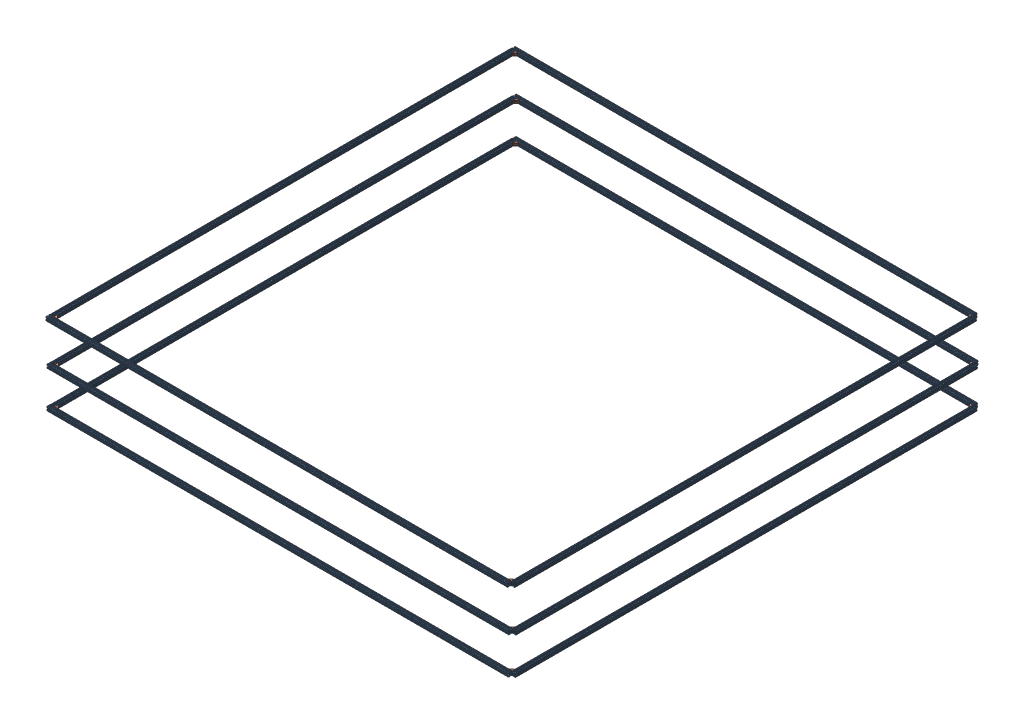
SolidWorks assembly Assem3, configuration Default. Lengths in mm.
Overall size (3082.56 533.4 3103.82).
315 component instances, 2 part files, 0 mates.
Components (placement in the parent):
- Rack Level-1: Rack Level [Default] at (101.9555 1672.9434 1770.6938) size (3070.95 28.09 3097.47)
  - big_connector_rod_24in-1: big_connector_rod_24in [Default] at origin size (25.4 25.4 3048)
    - connector_rod-1: connector_rod [Default] at (118.4239 27.3588 26.3342) size (25.4 25.4 127)
    - connector_rod-2: connector_rod [Default] at (118.4239 27.3588 -100.6658) size (25.4 25.4 127)
    - connector_rod-3: connector_rod [Default] at (118.4239 27.3588 -227.6658) size (25.4 25.4 127)
    - connector_rod-4: connector_rod [Default] at (118.4239 27.3588 -354.6658) size (25.4 25.4 127)
    - connector_rod-5: connector_rod [Default] at (118.4239 27.3588 153.3342) size (25.4 25.4 127)
    - connector_rod-6: connector_rod [Default] at (118.4239 27.3588 280.3342) size (25.4 25.4 127)
    - connector_rod-7: connector_rod [Default] at (118.4239 27.3588 407.3342) size (25.4 25.4 127)
    - connector_rod-8: connector_rod [Default] at (118.4239 27.3588 -481.6658) size (25.4 25.4 127)
    - connector_rod-9: connector_rod [Default] at (118.4239 27.3588 -608.6658) size (25.4 25.4 127)
    - connector_rod-10: connector_rod [Default] at (118.4239 27.3588 -862.6658) size (25.4 25.4 127)
    - connector_rod-11: connector_rod [Default] at (118.4239 27.3588 -735.6658) size (25.4 25.4 127)
    - connector_rod-12: connector_rod [Default] at (118.4239 27.3588 788.3342) size (25.4 25.4 127)
    - connector_rod-13: connector_rod [Default] at (118.4239 27.3588 534.3342) size (25.4 25.4 127)
    - connector_rod-14: connector_rod [Default] at (118.4239 27.3588 915.3342) x (-1 0 0) z (0 0 -1) size (25.4 25.4 127)
    - connector_rod-15: connector_rod [Default] at (118.4239 27.3588 915.3342) size (25.4 25.4 127)
    - connector_rod-16: connector_rod [Default] at (118.4239 27.3588 661.3342) size (25.4 25.4 127)
    - connector_rod-17: connector_rod [Default] at (118.4239 27.3588 1042.3342) x (-1 0 0) z (0 0 -1) size (25.4 25.4 127)
    - connector_rod-18: connector_rod [Default] at (118.4239 27.3588 1296.3342) size (25.4 25.4 127)
    - connector_rod-19: connector_rod [Default] at (118.4239 27.3588 -1116.6658) x (-1 0 0) z (0 0 -1) size (25.4 25.4 127)
    - connector_rod-20: connector_rod [Default] at (118.4239 27.3588 -1370.6658) x (-1 0 0) z (0 0 -1) size (25.4 25.4 127)
    - connector_rod-21: connector_rod [Default] at (118.4239 27.3588 1296.3342) x (-1 0 0) z (0 0 -1) size (25.4 25.4 127)
    - connector_rod-22: connector_rod [Default] at (118.4239 27.3588 -1243.6658) x (-1 0 0) z (0 0 -1) size (25.4 25.4 127)
    - connector_rod-23: connector_rod [Default] at (118.4239 27.3588 1423.3342) x (-1 0 0) z (0 0 -1) size (25.4 25.4 127)
    - connector_rod-24: connector_rod [Default] at (118.4239 27.3588 1550.3342) x (-1 0 0) z (0 0 -1) size (25.4 25.4 127)
  - big_connector_rod_24in-5: big_connector_rod_24in [Default] at (1475.8697 0 1807.1242) x (0 0 -1) z (1 0 0) size (25.4 25.4 3048)
    - connector_rod-1: connector_rod [Default] at (118.4239 27.3588 26.3342) size (25.4 25.4 127)
    - connector_rod-2: connector_rod [Default] at (118.4239 27.3588 -100.6658) size (25.4 25.4 127)
    - connector_rod-3: connector_rod [Default] at (118.4239 27.3588 -227.6658) size (25.4 25.4 127)
    - connector_rod-4: connector_rod [Default] at (118.4239 27.3588 -354.6658) size (25.4 25.4 127)
    - connector_rod-5: connector_rod [Default] at (118.4239 27.3588 153.3342) size (25.4 25.4 127)
    - connector_rod-6: connector_rod [Default] at (118.4239 27.3588 280.3342) size (25.4 25.4 127)
    - connector_rod-7: connector_rod [Default] at (118.4239 27.3588 407.3342) size (25.4 25.4 127)
    - connector_rod-8: connector_rod [Default] at (118.4239 27.3588 -481.6658) size (25.4 25.4 127)
    - connector_rod-9: connector_rod [Default] at (118.4239 27.3588 -608.6658) size (25.4 25.4 127)
    - connector_rod-10: connector_rod [Default] at (118.4239 27.3588 -862.6658) size (25.4 25.4 127)
    - connector_rod-11: connector_rod [Default] at (118.4239 27.3588 -735.6658) size (25.4 25.4 127)
    - connector_rod-12: connector_rod [Default] at (118.4239 27.3588 788.3342) size (25.4 25.4 127)
    - connector_rod-13: connector_rod [Default] at (118.4239 27.3588 534.3342) size (25.4 25.4 127)
    - connector_rod-14: connector_rod [Default] at (118.4239 27.3588 915.3342) x (-1 0 0) z (0 0 -1) size (25.4 25.4 127)
    - connector_rod-15: connector_rod [Default] at (118.4239 27.3588 915.3342) size (25.4 25.4 127)
    - connector_rod-16: connector_rod [Default] at (118.4239 27.3588 661.3342) size (25.4 25.4 127)
    - connector_rod-17: connector_rod [Default] at (118.4239 27.3588 1042.3342) x (-1 0 0) z (0 0 -1) size (25.4 25.4 127)
    - connector_rod-18: connector_rod [Default] at (118.4239 27.3588 1296.3342) size (25.4 25.4 127)
    - connector_rod-19: connector_rod [Default] at (118.4239 27.3588 -1116.6658) x (-1 0 0) z (0 0 -1) size (25.4 25.4 127)
    - connector_rod-20: connector_rod [Default] at (118.4239 27.3588 -1370.6658) x (-1 0 0) z (0 0 -1) size (25.4 25.4 127)
    - connector_rod-21: connector_rod [Default] at (118.4239 27.3588 1296.3342) x (-1 0 0) z (0 0 -1) size (25.4 25.4 127)
    - connector_rod-22: connector_rod [Default] at (118.4239 27.3588 -1243.6658) x (-1 0 0) z (0 0 -1) size (25.4 25.4 127)
    - connector_rod-23: connector_rod [Default] at (118.4239 27.3588 1423.3342) x (-1 0 0) z (0 0 -1) size (25.4 25.4 127)
    - connector_rod-24: connector_rod [Default] at (118.4239 27.3588 1550.3342) x (-1 0 0) z (0 0 -1) size (25.4 25.4 127)
  - big_connector_rod_24in-6: big_connector_rod_24in [Default] at (3045.03 -2.6868 -1.1586) size (25.4 25.4 3048)
    - connector_rod-1: connector_rod [Default] at (118.4239 27.3588 26.3342) size (25.4 25.4 127)
    - connector_rod-2: connector_rod [Default] at (118.4239 27.3588 -100.6658) size (25.4 25.4 127)
    - connector_rod-3: connector_rod [Default] at (118.4239 27.3588 -227.6658) size (25.4 25.4 127)
    - connector_rod-4: connector_rod [Default] at (118.4239 27.3588 -354.6658) size (25.4 25.4 127)
    - connector_rod-5: connector_rod [Default] at (118.4239 27.3588 153.3342) size (25.4 25.4 127)
    - connector_rod-6: connector_rod [Default] at (118.4239 27.3588 280.3342) size (25.4 25.4 127)
    - connector_rod-7: connector_rod [Default] at (118.4239 27.3588 407.3342) size (25.4 25.4 127)
    - connector_rod-8: connector_rod [Default] at (118.4239 27.3588 -481.6658) size (25.4 25.4 127)
    - connector_rod-9: connector_rod [Default] at (118.4239 27.3588 -608.6658) size (25.4 25.4 127)
    - connector_rod-10: connector_rod [Default] at (118.4239 27.3588 -862.6658) size (25.4 25.4 127)
    - connector_rod-11: connector_rod [Default] at (118.4239 27.3588 -735.6658) size (25.4 25.4 127)
    - connector_rod-12: connector_rod [Default] at (118.4239 27.3588 788.3342) size (25.4 25.4 127)
    - connector_rod-13: connector_rod [Default] at (118.4239 27.3588 534.3342) size (25.4 25.4 127)
    - connector_rod-14: connector_rod [Default] at (118.4239 27.3588 915.3342) x (-1 0 0) z (0 0 -1) size (25.4 25.4 127)
    - connector_rod-15: connector_rod [Default] at (118.4239 27.3588 915.3342) size (25.4 25.4 127)
    - connector_rod-16: connector_rod [Default] at (118.4239 27.3588 661.3342) size (25.4 25.4 127)
    - connector_rod-17: connector_rod [Default] at (118.4239 27.3588 1042.3342) x (-1 0 0) z (0 0 -1) size (25.4 25.4 127)
    - connector_rod-18: connector_rod [Default] at (118.4239 27.3588 1296.3342) size (25.4 25.4 127)
    - connector_rod-19: connector_rod [Default] at (118.4239 27.3588 -1116.6658) x (-1 0 0) z (0 0 -1) size (25.4 25.4 127)
    - connector_rod-20: connector_rod [Default] at (118.4239 27.3588 -1370.6658) x (-1 0 0) z (0 0 -1) size (25.4 25.4 127)
    - connector_rod-21: connector_rod [Default] at (118.4239 27.3588 1296.3342) x (-1 0 0) z (0 0 -1) size (25.4 25.4 127)
    - connector_rod-22: connector_rod [Default] at (118.4239 27.3588 -1243.6658) x (-1 0 0) z (0 0 -1) size (25.4 25.4 127)
    - connector_rod-23: connector_rod [Default] at (118.4239 27.3588 1423.3342) x (-1 0 0) z (0 0 -1) size (25.4 25.4 127)
    - connector_rod-24: connector_rod [Default] at (118.4239 27.3588 1550.3342) x (-1 0 0) z (0 0 -1) size (25.4 25.4 127)
  - big_connector_rod_24in-7: big_connector_rod_24in [Default] at (1477.9148 -2.6868 -1264.9419) x (0 0 -1) z (1 0 0) size (25.4 25.4 3048)
    - connector_rod-1: connector_rod [Default] at (118.4239 27.3588 26.3342) size (25.4 25.4 127)
    - connector_rod-2: connector_rod [Default] at (118.4239 27.3588 -100.6658) size (25.4 25.4 127)
    - connector_rod-3: connector_rod [Default] at (118.4239 27.3588 -227.6658) size (25.4 25.4 127)
    - connector_rod-4: connector_rod [Default] at (118.4239 27.3588 -354.6658) size (25.4 25.4 127)
    - connector_rod-5: connector_rod [Default] at (118.4239 27.3588 153.3342) size (25.4 25.4 127)
    - connector_rod-6: connector_rod [Default] at (118.4239 27.3588 280.3342) size (25.4 25.4 127)
    - connector_rod-7: connector_rod [Default] at (118.4239 27.3588 407.3342) size (25.4 25.4 127)
    - connector_rod-8: connector_rod [Default] at (118.4239 27.3588 -481.6658) size (25.4 25.4 127)
    - connector_rod-9: connector_rod [Default] at (118.4239 27.3588 -608.6658) size (25.4 25.4 127)
    - connector_rod-10: connector_rod [Default] at (118.4239 27.3588 -862.6658) size (25.4 25.4 127)
    - connector_rod-11: connector_rod [Default] at (118.4239 27.3588 -735.6658) size (25.4 25.4 127)
    - connector_rod-12: connector_rod [Default] at (118.4239 27.3588 788.3342) size (25.4 25.4 127)
    - connector_rod-13: connector_rod [Default] at (118.4239 27.3588 534.3342) size (25.4 25.4 127)
    - connector_rod-14: connector_rod [Default] at (118.4239 27.3588 915.3342) x (-1 0 0) z (0 0 -1) size (25.4 25.4 127)
    - connector_rod-15: connector_rod [Default] at (118.4239 27.3588 915.3342) size (25.4 25.4 127)
    - connector_rod-16: connector_rod [Default] at (118.4239 27.3588 661.3342) size (25.4 25.4 127)
    - connector_rod-17: connector_rod [Default] at (118.4239 27.3588 1042.3342) x (-1 0 0) z (0 0 -1) size (25.4 25.4 127)
    - connector_rod-18: connector_rod [Default] at (118.4239 27.3588 1296.3342) size (25.4 25.4 127)
    - connector_rod-19: connector_rod [Default] at (118.4239 27.3588 -1116.6658) x (-1 0 0) z (0 0 -1) size (25.4 25.4 127)
    - connector_rod-20: connector_rod [Default] at (118.4239 27.3588 -1370.6658) x (-1 0 0) z (0 0 -1) size (25.4 25.4 127)
    - connector_rod-21: connector_rod [Default] at (118.4239 27.3588 1296.3342) x (-1 0 0) z (0 0 -1) size (25.4 25.4 127)
    - connector_rod-22: connector_rod [Default] at (118.4239 27.3588 -1243.6658) x (-1 0 0) z (0 0 -1) size (25.4 25.4 127)
    - connector_rod-23: connector_rod [Default] at (118.4239 27.3588 1423.3342) x (-1 0 0) z (0 0 -1) size (25.4 25.4 127)
    - connector_rod-24: connector_rod [Default] at (118.4239 27.3588 1550.3342) x (-1 0 0) z (0 0 -1) size (25.4 25.4 127)
  - corner_bracket-1: corner_bracket [Default] at (131.1239 27.1203 -1370.6658) x (0 -1 0) z (0 0 1) size (17 21.5 21.5)
  - corner_bracket-2: corner_bracket [Default] at (131.1239 29.8071 1676.0002) x (0 1 0) z (0 0 -1) size (17 21.5 21.5)
  - corner_bracket-3: corner_bracket [Default] at (3150.7539 24.4335 -1370.6658) x (0 1 0) z (0 0 1) size (17 21.5 21.5)
  - corner_bracket-4: corner_bracket [Default] at (3150.7539 27.5973 1676.0002) x (0 1 0) z (-1 0 0) size (17 21.5 21.5)
- Rack Level-2: Rack Level [Default] at (104.6861 1434.333 1775.6813) size (3070.95 28.09 3097.47)
  - big_connector_rod_24in-1: big_connector_rod_24in [Default] at origin size (25.4 25.4 3048)
    - connector_rod-1: connector_rod [Default] at (118.4239 27.3588 26.3342) size (25.4 25.4 127)
    - connector_rod-2: connector_rod [Default] at (118.4239 27.3588 -100.6658) size (25.4 25.4 127)
    - connector_rod-3: connector_rod [Default] at (118.4239 27.3588 -227.6658) size (25.4 25.4 127)
    - connector_rod-4: connector_rod [Default] at (118.4239 27.3588 -354.6658) size (25.4 25.4 127)
    - connector_rod-5: connector_rod [Default] at (118.4239 27.3588 153.3342) size (25.4 25.4 127)
    - connector_rod-6: connector_rod [Default] at (118.4239 27.3588 280.3342) size (25.4 25.4 127)
    - connector_rod-7: connector_rod [Default] at (118.4239 27.3588 407.3342) size (25.4 25.4 127)
    - connector_rod-8: connector_rod [Default] at (118.4239 27.3588 -481.6658) size (25.4 25.4 127)
    - connector_rod-9: connector_rod [Default] at (118.4239 27.3588 -608.6658) size (25.4 25.4 127)
    - connector_rod-10: connector_rod [Default] at (118.4239 27.3588 -862.6658) size (25.4 25.4 127)
    - connector_rod-11: connector_rod [Default] at (118.4239 27.3588 -735.6658) size (25.4 25.4 127)
    - connector_rod-12: connector_rod [Default] at (118.4239 27.3588 788.3342) size (25.4 25.4 127)
    - connector_rod-13: connector_rod [Default] at (118.4239 27.3588 534.3342) size (25.4 25.4 127)
    - connector_rod-14: connector_rod [Default] at (118.4239 27.3588 915.3342) x (-1 0 0) z (0 0 -1) size (25.4 25.4 127)
    - connector_rod-15: connector_rod [Default] at (118.4239 27.3588 915.3342) size (25.4 25.4 127)
    - connector_rod-16: connector_rod [Default] at (118.4239 27.3588 661.3342) size (25.4 25.4 127)
    - connector_rod-17: connector_rod [Default] at (118.4239 27.3588 1042.3342) x (-1 0 0) z (0 0 -1) size (25.4 25.4 127)
    - connector_rod-18: connector_rod [Default] at (118.4239 27.3588 1296.3342) size (25.4 25.4 127)
    - connector_rod-19: connector_rod [Default] at (118.4239 27.3588 -1116.6658) x (-1 0 0) z (0 0 -1) size (25.4 25.4 127)
    - connector_rod-20: connector_rod [Default] at (118.4239 27.3588 -1370.6658) x (-1 0 0) z (0 0 -1) size (25.4 25.4 127)
    - connector_rod-21: connector_rod [Default] at (118.4239 27.3588 1296.3342) x (-1 0 0) z (0 0 -1) size (25.4 25.4 127)
    - connector_rod-22: connector_rod [Default] at (118.4239 27.3588 -1243.6658) x (-1 0 0) z (0 0 -1) size (25.4 25.4 127)
    - connector_rod-23: connector_rod [Default] at (118.4239 27.3588 1423.3342) x (-1 0 0) z (0 0 -1) size (25.4 25.4 127)
    - connector_rod-24: connector_rod [Default] at (118.4239 27.3588 1550.3342) x (-1 0 0) z (0 0 -1) size (25.4 25.4 127)
  - big_connector_rod_24in-5: big_connector_rod_24in [Default] at (1475.8697 0 1807.1242) x (0 0 -1) z (1 0 0) size (25.4 25.4 3048)
    - connector_rod-1: connector_rod [Default] at (118.4239 27.3588 26.3342) size (25.4 25.4 127)
    - connector_rod-2: connector_rod [Default] at (118.4239 27.3588 -100.6658) size (25.4 25.4 127)
    - connector_rod-3: connector_rod [Default] at (118.4239 27.3588 -227.6658) size (25.4 25.4 127)
    - connector_rod-4: connector_rod [Default] at (118.4239 27.3588 -354.6658) size (25.4 25.4 127)
    - connector_rod-5: connector_rod [Default] at (118.4239 27.3588 153.3342) size (25.4 25.4 127)
    - connector_rod-6: connector_rod [Default] at (118.4239 27.3588 280.3342) size (25.4 25.4 127)
    - connector_rod-7: connector_rod [Default] at (118.4239 27.3588 407.3342) size (25.4 25.4 127)
    - connector_rod-8: connector_rod [Default] at (118.4239 27.3588 -481.6658) size (25.4 25.4 127)
    - connector_rod-9: connector_rod [Default] at (118.4239 27.3588 -608.6658) size (25.4 25.4 127)
    - connector_rod-10: connector_rod [Default] at (118.4239 27.3588 -862.6658) size (25.4 25.4 127)
    - connector_rod-11: connector_rod [Default] at (118.4239 27.3588 -735.6658) size (25.4 25.4 127)
    - connector_rod-12: connector_rod [Default] at (118.4239 27.3588 788.3342) size (25.4 25.4 127)
    - connector_rod-13: connector_rod [Default] at (118.4239 27.3588 534.3342) size (25.4 25.4 127)
    - connector_rod-14: connector_rod [Default] at (118.4239 27.3588 915.3342) x (-1 0 0) z (0 0 -1) size (25.4 25.4 127)
    - connector_rod-15: connector_rod [Default] at (118.4239 27.3588 915.3342) size (25.4 25.4 127)
    - connector_rod-16: connector_rod [Default] at (118.4239 27.3588 661.3342) size (25.4 25.4 127)
    - connector_rod-17: connector_rod [Default] at (118.4239 27.3588 1042.3342) x (-1 0 0) z (0 0 -1) size (25.4 25.4 127)
    - connector_rod-18: connector_rod [Default] at (118.4239 27.3588 1296.3342) size (25.4 25.4 127)
    - connector_rod-19: connector_rod [Default] at (118.4239 27.3588 -1116.6658) x (-1 0 0) z (0 0 -1) size (25.4 25.4 127)
    - connector_rod-20: connector_rod [Default] at (118.4239 27.3588 -1370.6658) x (-1 0 0) z (0 0 -1) size (25.4 25.4 127)
    - connector_rod-21: connector_rod [Default] at (118.4239 27.3588 1296.3342) x (-1 0 0) z (0 0 -1) size (25.4 25.4 127)
    - connector_rod-22: connector_rod [Default] at (118.4239 27.3588 -1243.6658) x (-1 0 0) z (0 0 -1) size (25.4 25.4 127)
    - connector_rod-23: connector_rod [Default] at (118.4239 27.3588 1423.3342) x (-1 0 0) z (0 0 -1) size (25.4 25.4 127)
    - connector_rod-24: connector_rod [Default] at (118.4239 27.3588 1550.3342) x (-1 0 0) z (0 0 -1) size (25.4 25.4 127)
  - big_connector_rod_24in-6: big_connector_rod_24in [Default] at (3045.03 -2.6868 -1.1586) size (25.4 25.4 3048)
    - connector_rod-1: connector_rod [Default] at (118.4239 27.3588 26.3342) size (25.4 25.4 127)
    - connector_rod-2: connector_rod [Default] at (118.4239 27.3588 -100.6658) size (25.4 25.4 127)
    - connector_rod-3: connector_rod [Default] at (118.4239 27.3588 -227.6658) size (25.4 25.4 127)
    - connector_rod-4: connector_rod [Default] at (118.4239 27.3588 -354.6658) size (25.4 25.4 127)
    - connector_rod-5: connector_rod [Default] at (118.4239 27.3588 153.3342) size (25.4 25.4 127)
    - connector_rod-6: connector_rod [Default] at (118.4239 27.3588 280.3342) size (25.4 25.4 127)
    - connector_rod-7: connector_rod [Default] at (118.4239 27.3588 407.3342) size (25.4 25.4 127)
    - connector_rod-8: connector_rod [Default] at (118.4239 27.3588 -481.6658) size (25.4 25.4 127)
    - connector_rod-9: connector_rod [Default] at (118.4239 27.3588 -608.6658) size (25.4 25.4 127)
    - connector_rod-10: connector_rod [Default] at (118.4239 27.3588 -862.6658) size (25.4 25.4 127)
    - connector_rod-11: connector_rod [Default] at (118.4239 27.3588 -735.6658) size (25.4 25.4 127)
    - connector_rod-12: connector_rod [Default] at (118.4239 27.3588 788.3342) size (25.4 25.4 127)
    - connector_rod-13: connector_rod [Default] at (118.4239 27.3588 534.3342) size (25.4 25.4 127)
    - connector_rod-14: connector_rod [Default] at (118.4239 27.3588 915.3342) x (-1 0 0) z (0 0 -1) size (25.4 25.4 127)
    - connector_rod-15: connector_rod [Default] at (118.4239 27.3588 915.3342) size (25.4 25.4 127)
    - connector_rod-16: connector_rod [Default] at (118.4239 27.3588 661.3342) size (25.4 25.4 127)
    - connector_rod-17: connector_rod [Default] at (118.4239 27.3588 1042.3342) x (-1 0 0) z (0 0 -1) size (25.4 25.4 127)
    - connector_rod-18: connector_rod [Default] at (118.4239 27.3588 1296.3342) size (25.4 25.4 127)
    - connector_rod-19: connector_rod [Default] at (118.4239 27.3588 -1116.6658) x (-1 0 0) z (0 0 -1) size (25.4 25.4 127)
    - connector_rod-20: connector_rod [Default] at (118.4239 27.3588 -1370.6658) x (-1 0 0) z (0 0 -1) size (25.4 25.4 127)
    - connector_rod-21: connector_rod [Default] at (118.4239 27.3588 1296.3342) x (-1 0 0) z (0 0 -1) size (25.4 25.4 127)
    - connector_rod-22: connector_rod [Default] at (118.4239 27.3588 -1243.6658) x (-1 0 0) z (0 0 -1) size (25.4 25.4 127)
    - connector_rod-23: connector_rod [Default] at (118.4239 27.3588 1423.3342) x (-1 0 0) z (0 0 -1) size (25.4 25.4 127)
    - connector_rod-24: connector_rod [Default] at (118.4239 27.3588 1550.3342) x (-1 0 0) z (0 0 -1) size (25.4 25.4 127)
  - big_connector_rod_24in-7: big_connector_rod_24in [Default] at (1477.9148 -2.6868 -1264.9419) x (0 0 -1) z (1 0 0) size (25.4 25.4 3048)
    - connector_rod-1: connector_rod [Default] at (118.4239 27.3588 26.3342) size (25.4 25.4 127)
    - connector_rod-2: connector_rod [Default] at (118.4239 27.3588 -100.6658) size (25.4 25.4 127)
    - connector_rod-3: connector_rod [Default] at (118.4239 27.3588 -227.6658) size (25.4 25.4 127)
    - connector_rod-4: connector_rod [Default] at (118.4239 27.3588 -354.6658) size (25.4 25.4 127)
    - connector_rod-5: connector_rod [Default] at (118.4239 27.3588 153.3342) size (25.4 25.4 127)
    - connector_rod-6: connector_rod [Default] at (118.4239 27.3588 280.3342) size (25.4 25.4 127)
    - connector_rod-7: connector_rod [Default] at (118.4239 27.3588 407.3342) size (25.4 25.4 127)
    - connector_rod-8: connector_rod [Default] at (118.4239 27.3588 -481.6658) size (25.4 25.4 127)
    - connector_rod-9: connector_rod [Default] at (118.4239 27.3588 -608.6658) size (25.4 25.4 127)
    - connector_rod-10: connector_rod [Default] at (118.4239 27.3588 -862.6658) size (25.4 25.4 127)
    - connector_rod-11: connector_rod [Default] at (118.4239 27.3588 -735.6658) size (25.4 25.4 127)
    - connector_rod-12: connector_rod [Default] at (118.4239 27.3588 788.3342) size (25.4 25.4 127)
    - connector_rod-13: connector_rod [Default] at (118.4239 27.3588 534.3342) size (25.4 25.4 127)
    - connector_rod-14: connector_rod [Default] at (118.4239 27.3588 915.3342) x (-1 0 0) z (0 0 -1) size (25.4 25.4 127)
    - connector_rod-15: connector_rod [Default] at (118.4239 27.3588 915.3342) size (25.4 25.4 127)
    - connector_rod-16: connector_rod [Default] at (118.4239 27.3588 661.3342) size (25.4 25.4 127)
    - connector_rod-17: connector_rod [Default] at (118.4239 27.3588 1042.3342) x (-1 0 0) z (0 0 -1) size (25.4 25.4 127)
    - connector_rod-18: connector_rod [Default] at (118.4239 27.3588 1296.3342) size (25.4 25.4 127)
    - connector_rod-19: connector_rod [Default] at (118.4239 27.3588 -1116.6658) x (-1 0 0) z (0 0 -1) size (25.4 25.4 127)
    - connector_rod-20: connector_rod [Default] at (118.4239 27.3588 -1370.6658) x (-1 0 0) z (0 0 -1) size (25.4 25.4 127)
    - connector_rod-21: connector_rod [Default] at (118.4239 27.3588 1296.3342) x (-1 0 0) z (0 0 -1) size (25.4 25.4 127)
    - connector_rod-22: connector_rod [Default] at (118.4239 27.3588 -1243.6658) x (-1 0 0) z (0 0 -1) size (25.4 25.4 127)
    - connector_rod-23: connector_rod [Default] at (118.4239 27.3588 1423.3342) x (-1 0 0) z (0 0 -1) size (25.4 25.4 127)
    - connector_rod-24: connector_rod [Default] at (118.4239 27.3588 1550.3342) x (-1 0 0) z (0 0 -1) size (25.4 25.4 127)
  - corner_bracket-1: corner_bracket [Default] at (131.1239 27.1203 -1370.6658) x (0 -1 0) z (0 0 1) size (17 21.5 21.5)
  - corner_bracket-2: corner_bracket [Default] at (131.1239 29.8071 1676.0002) x (0 1 0) z (0 0 -1) size (17 21.5 21.5)
  - corner_bracket-3: corner_bracket [Default] at (3150.7539 24.4335 -1370.6658) x (0 1 0) z (0 0 1) size (17 21.5 21.5)
  - corner_bracket-4: corner_bracket [Default] at (3150.7539 27.5973 1676.0002) x (0 1 0) z (-1 0 0) size (17 21.5 21.5)
- Rack Level-4: Rack Level [Default] at (93.0717 1939.6417 1769.3236) size (3070.95 28.09 3097.47)
  - big_connector_rod_24in-1: big_connector_rod_24in [Default] at origin size (25.4 25.4 3048)
    - connector_rod-1: connector_rod [Default] at (118.4239 27.3588 26.3342) size (25.4 25.4 127)
    - connector_rod-2: connector_rod [Default] at (118.4239 27.3588 -100.6658) size (25.4 25.4 127)
    - connector_rod-3: connector_rod [Default] at (118.4239 27.3588 -227.6658) size (25.4 25.4 127)
    - connector_rod-4: connector_rod [Default] at (118.4239 27.3588 -354.6658) size (25.4 25.4 127)
    - connector_rod-5: connector_rod [Default] at (118.4239 27.3588 153.3342) size (25.4 25.4 127)
    - connector_rod-6: connector_rod [Default] at (118.4239 27.3588 280.3342) size (25.4 25.4 127)
    - connector_rod-7: connector_rod [Default] at (118.4239 27.3588 407.3342) size (25.4 25.4 127)
    - connector_rod-8: connector_rod [Default] at (118.4239 27.3588 -481.6658) size (25.4 25.4 127)
    - connector_rod-9: connector_rod [Default] at (118.4239 27.3588 -608.6658) size (25.4 25.4 127)
    - connector_rod-10: connector_rod [Default] at (118.4239 27.3588 -862.6658) size (25.4 25.4 127)
    - connector_rod-11: connector_rod [Default] at (118.4239 27.3588 -735.6658) size (25.4 25.4 127)
    - connector_rod-12: connector_rod [Default] at (118.4239 27.3588 788.3342) size (25.4 25.4 127)
    - connector_rod-13: connector_rod [Default] at (118.4239 27.3588 534.3342) size (25.4 25.4 127)
    - connector_rod-14: connector_rod [Default] at (118.4239 27.3588 915.3342) x (-1 0 0) z (0 0 -1) size (25.4 25.4 127)
    - connector_rod-15: connector_rod [Default] at (118.4239 27.3588 915.3342) size (25.4 25.4 127)
    - connector_rod-16: connector_rod [Default] at (118.4239 27.3588 661.3342) size (25.4 25.4 127)
    - connector_rod-17: connector_rod [Default] at (118.4239 27.3588 1042.3342) x (-1 0 0) z (0 0 -1) size (25.4 25.4 127)
    - connector_rod-18: connector_rod [Default] at (118.4239 27.3588 1296.3342) size (25.4 25.4 127)
    - connector_rod-19: connector_rod [Default] at (118.4239 27.3588 -1116.6658) x (-1 0 0) z (0 0 -1) size (25.4 25.4 127)
    - connector_rod-20: connector_rod [Default] at (118.4239 27.3588 -1370.6658) x (-1 0 0) z (0 0 -1) size (25.4 25.4 127)
    - connector_rod-21: connector_rod [Default] at (118.4239 27.3588 1296.3342) x (-1 0 0) z (0 0 -1) size (25.4 25.4 127)
    - connector_rod-22: connector_rod [Default] at (118.4239 27.3588 -1243.6658) x (-1 0 0) z (0 0 -1) size (25.4 25.4 127)
    - connector_rod-23: connector_rod [Default] at (118.4239 27.3588 1423.3342) x (-1 0 0) z (0 0 -1) size (25.4 25.4 127)
    - connector_rod-24: connector_rod [Default] at (118.4239 27.3588 1550.3342) x (-1 0 0) z (0 0 -1) size (25.4 25.4 127)
  - big_connector_rod_24in-5: big_connector_rod_24in [Default] at (1475.8697 0 1807.1242) x (0 0 -1) z (1 0 0) size (25.4 25.4 3048)
    - connector_rod-1: connector_rod [Default] at (118.4239 27.3588 26.3342) size (25.4 25.4 127)
    - connector_rod-2: connector_rod [Default] at (118.4239 27.3588 -100.6658) size (25.4 25.4 127)
    - connector_rod-3: connector_rod [Default] at (118.4239 27.3588 -227.6658) size (25.4 25.4 127)
    - connector_rod-4: connector_rod [Default] at (118.4239 27.3588 -354.6658) size (25.4 25.4 127)
    - connector_rod-5: connector_rod [Default] at (118.4239 27.3588 153.3342) size (25.4 25.4 127)
    - connector_rod-6: connector_rod [Default] at (118.4239 27.3588 280.3342) size (25.4 25.4 127)
    - connector_rod-7: connector_rod [Default] at (118.4239 27.3588 407.3342) size (25.4 25.4 127)
    - connector_rod-8: connector_rod [Default] at (118.4239 27.3588 -481.6658) size (25.4 25.4 127)
    - connector_rod-9: connector_rod [Default] at (118.4239 27.3588 -608.6658) size (25.4 25.4 127)
    - connector_rod-10: connector_rod [Default] at (118.4239 27.3588 -862.6658) size (25.4 25.4 127)
    - connector_rod-11: connector_rod [Default] at (118.4239 27.3588 -735.6658) size (25.4 25.4 127)
    - connector_rod-12: connector_rod [Default] at (118.4239 27.3588 788.3342) size (25.4 25.4 127)
    - connector_rod-13: connector_rod [Default] at (118.4239 27.3588 534.3342) size (25.4 25.4 127)
    - connector_rod-14: connector_rod [Default] at (118.4239 27.3588 915.3342) x (-1 0 0) z (0 0 -1) size (25.4 25.4 127)
    - connector_rod-15: connector_rod [Default] at (118.4239 27.3588 915.3342) size (25.4 25.4 127)
    - connector_rod-16: connector_rod [Default] at (118.4239 27.3588 661.3342) size (25.4 25.4 127)
    - connector_rod-17: connector_rod [Default] at (118.4239 27.3588 1042.3342) x (-1 0 0) z (0 0 -1) size (25.4 25.4 127)
    - connector_rod-18: connector_rod [Default] at (118.4239 27.3588 1296.3342) size (25.4 25.4 127)
    - connector_rod-19: connector_rod [Default] at (118.4239 27.3588 -1116.6658) x (-1 0 0) z (0 0 -1) size (25.4 25.4 127)
    - connector_rod-20: connector_rod [Default] at (118.4239 27.3588 -1370.6658) x (-1 0 0) z (0 0 -1) size (25.4 25.4 127)
    - connector_rod-21: connector_rod [Default] at (118.4239 27.3588 1296.3342) x (-1 0 0) z (0 0 -1) size (25.4 25.4 127)
    - connector_rod-22: connector_rod [Default] at (118.4239 27.3588 -1243.6658) x (-1 0 0) z (0 0 -1) size (25.4 25.4 127)
    - connector_rod-23: connector_rod [Default] at (118.4239 27.3588 1423.3342) x (-1 0 0) z (0 0 -1) size (25.4 25.4 127)
    - connector_rod-24: connector_rod [Default] at (118.4239 27.3588 1550.3342) x (-1 0 0) z (0 0 -1) size (25.4 25.4 127)
  - big_connector_rod_24in-6: big_connector_rod_24in [Default] at (3045.03 -2.6868 -1.1586) size (25.4 25.4 3048)
    - connector_rod-1: connector_rod [Default] at (118.4239 27.3588 26.3342) size (25.4 25.4 127)
    - connector_rod-2: connector_rod [Default] at (118.4239 27.3588 -100.6658) size (25.4 25.4 127)
    - connector_rod-3: connector_rod [Default] at (118.4239 27.3588 -227.6658) size (25.4 25.4 127)
    - connector_rod-4: connector_rod [Default] at (118.4239 27.3588 -354.6658) size (25.4 25.4 127)
    - connector_rod-5: connector_rod [Default] at (118.4239 27.3588 153.3342) size (25.4 25.4 127)
    - connector_rod-6: connector_rod [Default] at (118.4239 27.3588 280.3342) size (25.4 25.4 127)
    - connector_rod-7: connector_rod [Default] at (118.4239 27.3588 407.3342) size (25.4 25.4 127)
    - connector_rod-8: connector_rod [Default] at (118.4239 27.3588 -481.6658) size (25.4 25.4 127)
    - connector_rod-9: connector_rod [Default] at (118.4239 27.3588 -608.6658) size (25.4 25.4 127)
    - connector_rod-10: connector_rod [Default] at (118.4239 27.3588 -862.6658) size (25.4 25.4 127)
    - connector_rod-11: connector_rod [Default] at (118.4239 27.3588 -735.6658) size (25.4 25.4 127)
    - connector_rod-12: connector_rod [Default] at (118.4239 27.3588 788.3342) size (25.4 25.4 127)
    - connector_rod-13: connector_rod [Default] at (118.4239 27.3588 534.3342) size (25.4 25.4 127)
    - connector_rod-14: connector_rod [Default] at (118.4239 27.3588 915.3342) x (-1 0 0) z (0 0 -1) size (25.4 25.4 127)
    - connector_rod-15: connector_rod [Default] at (118.4239 27.3588 915.3342) size (25.4 25.4 127)
    - connector_rod-16: connector_rod [Default] at (118.4239 27.3588 661.3342) size (25.4 25.4 127)
    - connector_rod-17: connector_rod [Default] at (118.4239 27.3588 1042.3342) x (-1 0 0) z (0 0 -1) size (25.4 25.4 127)
    - connector_rod-18: connector_rod [Default] at (118.4239 27.3588 1296.3342) size (25.4 25.4 127)
    - connector_rod-19: connector_rod [Default] at (118.4239 27.3588 -1116.6658) x (-1 0 0) z (0 0 -1) size (25.4 25.4 127)
    - connector_rod-20: connector_rod [Default] at (118.4239 27.3588 -1370.6658) x (-1 0 0) z (0 0 -1) size (25.4 25.4 127)
    - connector_rod-21: connector_rod [Default] at (118.4239 27.3588 1296.3342) x (-1 0 0) z (0 0 -1) size (25.4 25.4 127)
    - connector_rod-22: connector_rod [Default] at (118.4239 27.3588 -1243.6658) x (-1 0 0) z (0 0 -1) size (25.4 25.4 127)
    - connector_rod-23: connector_rod [Default] at (118.4239 27.3588 1423.3342) x (-1 0 0) z (0 0 -1) size (25.4 25.4 127)
    - connector_rod-24: connector_rod [Default] at (118.4239 27.3588 1550.3342) x (-1 0 0) z (0 0 -1) size (25.4 25.4 127)
  - big_connector_rod_24in-7: big_connector_rod_24in [Default] at (1477.9148 -2.6868 -1264.9419) x (0 0 -1) z (1 0 0) size (25.4 25.4 3048)
    - connector_rod-1: connector_rod [Default] at (118.4239 27.3588 26.3342) size (25.4 25.4 127)
    - connector_rod-2: connector_rod [Default] at (118.4239 27.3588 -100.6658) size (25.4 25.4 127)
    - connector_rod-3: connector_rod [Default] at (118.4239 27.3588 -227.6658) size (25.4 25.4 127)
    - connector_rod-4: connector_rod [Default] at (118.4239 27.3588 -354.6658) size (25.4 25.4 127)
    - connector_rod-5: connector_rod [Default] at (118.4239 27.3588 153.3342) size (25.4 25.4 127)
    - connector_rod-6: connector_rod [Default] at (118.4239 27.3588 280.3342) size (25.4 25.4 127)
    - connector_rod-7: connector_rod [Default] at (118.4239 27.3588 407.3342) size (25.4 25.4 127)
    - connector_rod-8: connector_rod [Default] at (118.4239 27.3588 -481.6658) size (25.4 25.4 127)
    - connector_rod-9: connector_rod [Default] at (118.4239 27.3588 -608.6658) size (25.4 25.4 127)
    - connector_rod-10: connector_rod [Default] at (118.4239 27.3588 -862.6658) size (25.4 25.4 127)
    - connector_rod-11: connector_rod [Default] at (118.4239 27.3588 -735.6658) size (25.4 25.4 127)
    - connector_rod-12: connector_rod [Default] at (118.4239 27.3588 788.3342) size (25.4 25.4 127)
    - connector_rod-13: connector_rod [Default] at (118.4239 27.3588 534.3342) size (25.4 25.4 127)
    - connector_rod-14: connector_rod [Default] at (118.4239 27.3588 915.3342) x (-1 0 0) z (0 0 -1) size (25.4 25.4 127)
    - connector_rod-15: connector_rod [Default] at (118.4239 27.3588 915.3342) size (25.4 25.4 127)
    - connector_rod-16: connector_rod [Default] at (118.4239 27.3588 661.3342) size (25.4 25.4 127)
    - connector_rod-17: connector_rod [Default] at (118.4239 27.3588 1042.3342) x (-1 0 0) z (0 0 -1) size (25.4 25.4 127)
    - connector_rod-18: connector_rod [Default] at (118.4239 27.3588 1296.3342) size (25.4 25.4 127)
    - connector_rod-19: connector_rod [Default] at (118.4239 27.3588 -1116.6658) x (-1 0 0) z (0 0 -1) size (25.4 25.4 127)
    - connector_rod-20: connector_rod [Default] at (118.4239 27.3588 -1370.6658) x (-1 0 0) z (0 0 -1) size (25.4 25.4 127)
    - connector_rod-21: connector_rod [Default] at (118.4239 27.3588 1296.3342) x (-1 0 0) z (0 0 -1) size (25.4 25.4 127)
    - connector_rod-22: connector_rod [Default] at (118.4239 27.3588 -1243.6658) x (-1 0 0) z (0 0 -1) size (25.4 25.4 127)
    - connector_rod-23: connector_rod [Default] at (118.4239 27.3588 1423.3342) x (-1 0 0) z (0 0 -1) size (25.4 25.4 127)
    - connector_rod-24: connector_rod [Default] at (118.4239 27.3588 1550.3342) x (-1 0 0) z (0 0 -1) size (25.4 25.4 127)
  - corner_bracket-1: corner_bracket [Default] at (131.1239 27.1203 -1370.6658) x (0 -1 0) z (0 0 1) size (17 21.5 21.5)
  - corner_bracket-2: corner_bracket [Default] at (131.1239 29.8071 1676.0002) x (0 1 0) z (0 0 -1) size (17 21.5 21.5)
  - corner_bracket-3: corner_bracket [Default] at (3150.7539 24.4335 -1370.6658) x (0 1 0) z (0 0 1) size (17 21.5 21.5)
  - corner_bracket-4: corner_bracket [Default] at (3150.7539 27.5973 1676.0002) x (0 1 0) z (-1 0 0) size (17 21.5 21.5)
